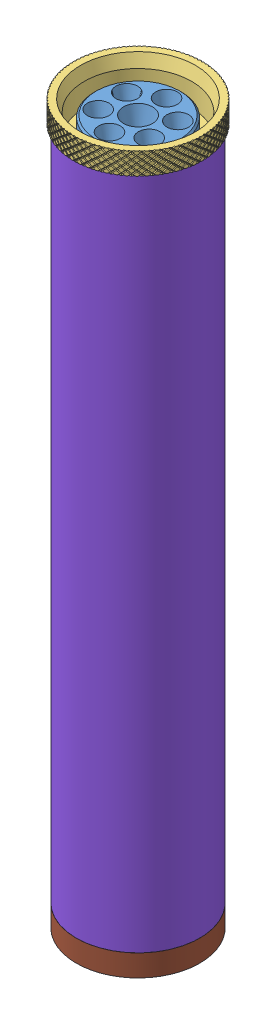
SolidWorks assembly S1B_Motor_and_Motor_Casing, configuration Default. Lengths in mm.
Overall size (66.27 314.35 66.27).
15 component instances, 11 part files, 29 mates.
Components (placement in the parent):
- S1B_Nozzle-1: S1B_Nozzle [Default] at (13.8939 -52.5907 243.3717) x (0.999876 0 -0.015724) z (-0.015724 0 -0.999876) size (50.55 26.47 50.55)
- S1B_ForwardSealDisk-1: S1B_ForwardSealDisk [Default] at (13.8939 -253.0725 243.3717) x (0.999998 0 0.001834) z (-0.001834 0 0.999998) size (50.4 6.2 50.4)
- S1B_S1AftClosure-1: S1B_S1AftClosure [Default] at (32.5939 -70.3251 243.3717) size (56.53 20.87 56.51)
- S1B_CaseSpacer-1: S1B_CaseSpacer [Default] at (13.8939 -342.4625 243.3717) x (0.984366 0 0.176137) z (-0.176137 0 0.984366) size (50.35 83.14 50.35)
- S1B_FloatingForwardClosure-1: S1B_FloatingForwardClosure [Default] at (13.8939 -253.0725 243.3717) x (0.109892 0 -0.993944) z (-0.993944 0 -0.109892) size (50 36.61 50)
- S1B_Liner-1: S1B_Liner [Default] at (13.8939 -249.7325 243.3717) x (0.217736 0 0.976008) z (-0.976008 0 0.217736) size (50.7 177.66 50.7)
- S1B_Grains CAD-1: S1B_Grains CAD [Default] at (13.8939 -246.8682 243.3717) x (0.314643 0 -0.94921) z (0.94921 0 0.314643) size (47 82.35 47)
- S1B_Casing-2: S1B_Casing [Default] at (13.8939 -351.0945 243.3717) size (54 295.28 54)
- S1B_Grains CAD-2: S1B_Grains CAD [Default] at (13.8939 -162.9237 243.3717) x (-0.810675 0 -0.585496) z (0.585496 0 -0.810675) size (47 82.35 47)
- S1B_O-ringL-1: S1B_O-ringL [9452K62] at (13.8939 -67.7195 243.3717) x (0.157366 0 0.98754) z (0 1 0) size (51.1 51.1 3.53)
- S1B_O-ringL-4: S1B_O-ringL [9452K62] at (13.8939 -254.5725 243.3717) x (0.948867 0 0.315675) z (0 1 0) size (51.1 51.1 3.53)
- S1B_9452K118_Oil-Resistant Buna-N O-Ring (031)-1: S1B_9452K118_Oil-Resistant Buna-N O-Ring (031) [9452K118] at (13.8939 -248.3325 243.3717) x (0.860014 0 0.510271) z (0 1 0) size (47.73 47.73 1.78)
- S1B_9452K118_Oil-Resistant Buna-N O-Ring (031)-2: S1B_9452K118_Oil-Resistant Buna-N O-Ring (031) [9452K118] at (13.8939 -79.7075 243.3717) x (-0.052255 0 0.998634) z (0 1 0) size (47.73 47.73 1.78)
- S1B_9452K118_Oil-Resistant Buna-N O-Ring (031)-3: S1B_9452K118_Oil-Resistant Buna-N O-Ring (031) [9452K118] at (13.8939 -163.8682 243.3717) x (0.996802 0 0.079916) z (0 1 0) size (47.73 47.73 1.78)
- S1B_S1AftClosure - Copy-1: S1B_S1AftClosure - Copy [Default] at (8.9907 -336.5889 261.4174) x (-0.262202 0 0.965013) z (0.965013 0 0.262202) size (54 20.81 54)
Mates (geometry in assembly coordinates):
- Concentric2: concentric anti-aligned: cylinder of S1BNozzle-1 through (13.8939 -52.5907 243.3717) axis (0 1 0) radius 19.05; cylinder of S1AftClosure-1 through (13.8939 -62.8889 243.3717) axis (0 -1 0) radius 25.35
- Coincident1: coincident anti-aligned: plane of S1BNozzle-1 through (13.8939 -67.1195 243.3717) normal (0 1 0); plane of S1AftClosure-1 through (32.5939 -67.1195 243.3717) normal (0 -1 0)
- Concentric3: concentric anti-aligned: cylinder of S1BNozzle-1 through (13.8939 -52.5907 243.3717) axis (0 1 0) radius 23.7744; cylinder of S1Casing-2 through (13.8939 -55.8195 243.3717) axis (0 -1 0) radius 27
- Coincident2: coincident anti-aligned: plane of S1AftClosure-1 through (32.5939 -55.8195 243.3717) normal (0 -1 0); plane of S1Casing-2 through (13.8939 -55.8195 243.3717) normal (0 1 0)
- Concentric4: concentric anti-aligned: cylinder of S1BNozzle-1 through (13.8939 -52.5907 243.3717) axis (0 1 0) radius 23.7744; cylinder of S1Liner-1 through (13.8939 -72.0725 243.3717) axis (0 -1 0) radius 25.35
- Coincident3: coincident anti-aligned: plane of S1BNozzle-1 through (13.8939 -72.0725 243.3717) normal (0 -1 0); plane of S1Liner-1 through (13.8939 -72.0725 243.3717) normal (0 1 0)
- Concentric5: concentric aligned: cylinder of S1Liner-1 through (13.8939 -72.0725 243.3717) axis (0 -1 0) radius 23.5; cylinder of Grains CAD-1 through (13.8939 -164.5182 243.3717) axis (0 -1 0) radius 23.5
- Concentric6: concentric aligned: cylinder of Grains CAD-1 through (13.8939 -264.5182 243.3717) axis (0 1 0) radius 9; cylinder of Grains CAD-2 through (13.8939 -180.5737 243.3717) axis (0 1 0) radius 9
- Concentric7: concentric aligned: cylinder of ForwardSealDisk-1 through (13.8939 -253.0725 243.3717) axis (0 -1 0) radius 25.2; cylinder of S1Liner-1 through (13.8939 -72.0725 243.3717) axis (0 -1 0) radius 25.35
- Concentric10: concentric anti-aligned: cylinder of S1Casing-2 through (13.8939 -55.8195 243.3717) axis (0 -1 0) radius 25.35; cylinder of S1AftClosure-2 through (13.8939 -344.0251 243.3717) axis (0 1 0) radius 25.35
- Coincident7: coincident anti-aligned: plane of S1Casing-2 through (13.8939 -351.0945 243.3717) normal (0 -1 0); plane of S1AftClosure-2 through (32.5933 -351.0945 243.2228) normal (0 1 0)
- Concentric12: concentric anti-aligned: cylinder of S1Liner-1 through (13.8939 -72.0725 243.3717) axis (0 -1 0) radius 25.35; line of O-ringL-1 through (13.8939 -67.7195 243.3717) axis (0 1 0)
- Concentric15: concentric anti-aligned: cylinder of Grains CAD-1 through (13.8939 -164.5182 243.3717) axis (0 -1 0) radius 23.5; line of O-ringL-4 through (13.8939 -254.5725 243.3717) axis (0 1 0)
- Concentric16: concentric anti-aligned: cylinder of Grains CAD-2 through (13.8939 -80.5737 243.3717) axis (0 -1 0) radius 23.5; line of 9452K118_Oil-Resistant Buna-N O-Ring (031)-1 through (13.8939 -248.3325 243.3717) axis (0 1 0)
- Concentric17: concentric anti-aligned: cylinder of Grains CAD-1 through (13.8939 -164.5182 243.3717) axis (0 -1 0) radius 23.5; line of 9452K118_Oil-Resistant Buna-N O-Ring (031)-2 through (13.8939 -79.7075 243.3717) axis (0 1 0)
- Concentric18: concentric anti-aligned: cylinder of Grains CAD-1 through (13.8939 -164.5182 243.3717) axis (0 -1 0) radius 23.5; line of 9452K118_Oil-Resistant Buna-N O-Ring (031)-3 through (13.8939 -163.8682 243.3717) axis (0 1 0)
- Distance2: distance = 1.6 mm anti-aligned: plane of O-ringL-1 through (13.8939 -67.7195 243.3717) normal (0 1 0); plane of S1AftClosure-1 through (32.5939 -66.1195 243.3717) normal (0 -1 0)
- Distance3: distance = 1.4 mm aligned: plane of 9452K118_Oil-Resistant Buna-N O-Ring (031)-1 through (13.8939 -248.3325 243.3717) normal (0 1 0); plane of ForwardSealDisk-1 through (13.8939 -249.7325 243.3717) normal (0 1 0)
- Concentric19: concentric anti-aligned: cylinder of S1FloatingForwardClosure-1 through (13.8939 -253.0725 243.3717) axis (0 1 0) radius 18.0356; cylinder of Grains CAD-1 through (13.8939 -164.5182 243.3717) axis (0 -1 0) radius 23.5
- Coincident12: coincident anti-aligned: plane of ForwardSealDisk-1 through (13.8939 -253.0725 243.3717) normal (0 -1 0); plane of S1FloatingForwardClosure-1 through (13.8939 -253.0725 243.3717) normal (0 1 0)
- Distance4: distance = 1.5 mm anti-aligned: plane of O-ringL-4 through (13.8939 -254.5725 243.3717) normal (0 1 0); plane of ForwardSealDisk-1 through (13.8939 -253.0725 243.3717) normal (0 -1 0)
- Coincident14: coincident anti-aligned: plane of ForwardSealDisk-1 through (13.8939 -246.8682 243.3717) normal (0 1 0); plane of Grains CAD-1 through (13.8939 -246.8682 243.3717) normal (0 -1 0)
- Distance5: distance = 0.65 mm aligned: plane of 9452K118_Oil-Resistant Buna-N O-Ring (031)-3 through (13.8939 -163.8682 243.3717) normal (0 1 0); plane of Grains CAD-1 through (13.8939 -164.5182 243.3717) normal (0 1 0)
- Concentric20: concentric aligned: cylinder of S1CaseSpacer-1 through (13.8939 -259.3225 243.3717) axis (0 -1 0) radius 25.175; cylinder of Grains CAD-1 through (13.8939 -164.5182 243.3717) axis (0 -1 0) radius 23.5
- Coincident16: coincident anti-aligned: circle of S1CaseSpacer-1; plane of S1FloatingForwardClosure-1 through (13.8939 -259.3225 243.3717) normal (0 -1 0)
- Distance6: distance = 0.65 mm anti-aligned: plane of 9452K118_Oil-Resistant Buna-N O-Ring (031)-2 through (13.8939 -79.7075 243.3717) normal (0 1 0); plane of S1BNozzle-1 through (13.8939 -79.0575 243.3717) normal (0 -1 0)
- Distance7: distance = 1.5162 mm anti-aligned: plane of Grains CAD-2 through (13.8939 -80.5737 243.3717) normal (0 1 0); plane of S1BNozzle-1 through (13.8939 -79.0575 243.3717) normal (0 -1 0)
- Concentric21: concentric anti-aligned: cylinder of S1Casing-2 through (13.8939 -55.8195 243.3717) axis (0 -1 0) radius 27; cylinder of S1AftClosure - Copy-1 through (13.8939 -344.0251 243.3717) axis (0 1 0) radius 25.35
- Coincident21: coincident anti-aligned: plane of S1Casing-2 through (13.8939 -351.0945 243.3717) normal (0 -1 0); plane of S1AftClosure - Copy-1 through (8.9907 -351.0945 261.4174) normal (0 1 0)
